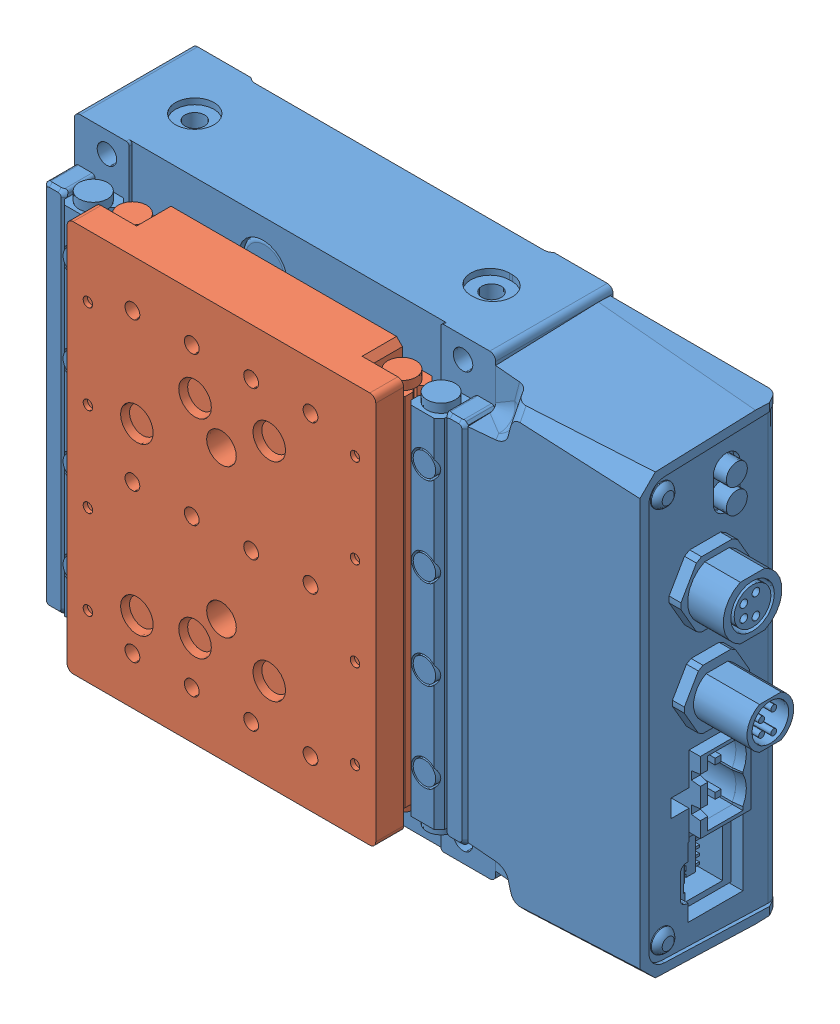
SolidWorks assembly DMA, configuration X-DMA10A-AE55ZJ2T17. Lengths in mm.
Overall size (110.42 77 30.5).
2 component instances, 2 part files, 9 mates.
Components (placement in the parent):
- DMA_base^DMA-1: DMA_base^DMA [X-DMA10A-Z] x (-1 0 0) z (0 1 0) size (110.42 25.8 77) (virtual)
- DMA_carriage^DMA-1: DMA_carriage^DMA [Default] x (-1 0 0) z (0 1 0) (virtual)
Mates (geometry in assembly coordinates):
- Coincident1: coincident aligned: plane of DMA_base^DMA-1 through (0 0 0) normal (0 0 1); plane of DMA_carriage-1 through (0 0 0) normal (0 0 1)
- Coincident2: coincident aligned: plane of DMA_base^DMA-1 through (0 0 0) normal (-1 0 0); plane of DMA_carriage-1 through (0 0 0) normal (-1 0 0)
- LimitDistance1: limit distance = 0 mm aligned: plane of Copy of DMA_carriage^DMA-1 through (0 0 0) normal (0 1 0); plane of DMA_base^DMA-1 through (0 0 0) normal (0 1 0)
- Coincident3: coincident aligned: line of Copy of DMA_base^DMA-1 through (-42.35 0 0) axis (0 0 1)
- Coincident4: coincident aligned: plane of Copy of DMA_base^DMA-1 through (0 0 0) normal (1 0 0)
- Coincident5: coincident aligned: unknown of Copy of DMA_base^DMA-1
- Coincident6: coincident aligned: plane of DMA_base^DMA-1 through (0 0 0) normal (0 0 1)
- Coincident7: coincident aligned: plane of DMA_base^DMA-1 through (0 0 0) normal (0 1 0)
- Coincident8: coincident anti-aligned: plane of DMA_base^DMA-1 through (0 0 0) normal (-1 0 0)
